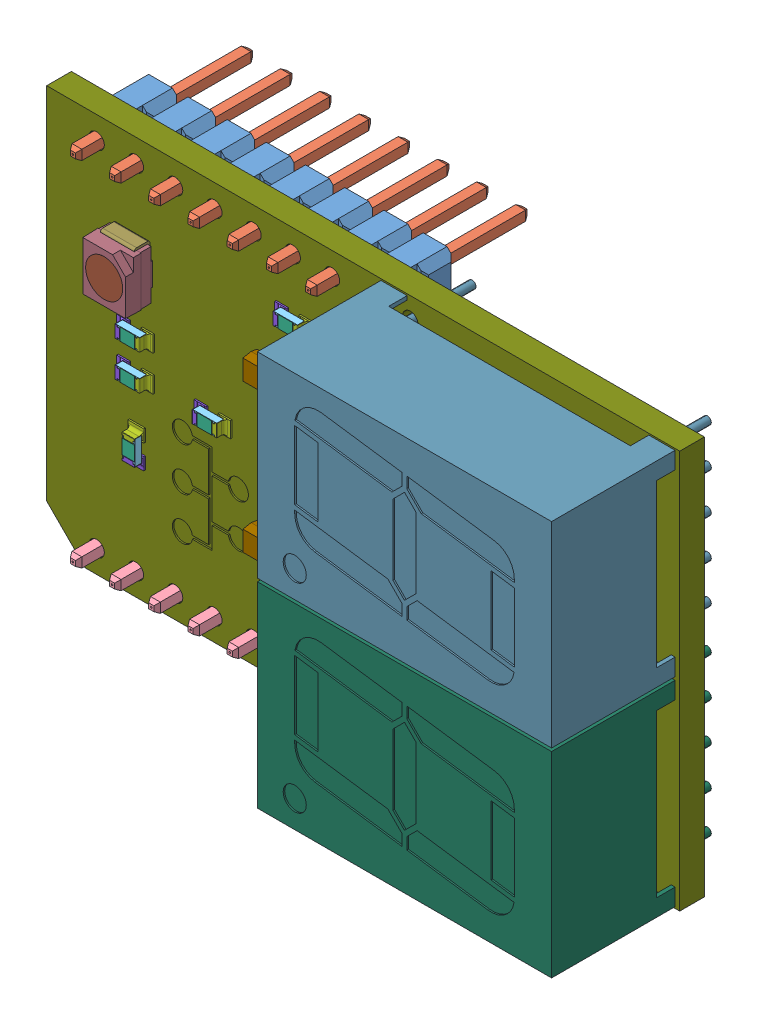
SolidWorks assembly mikroBUS_7_Seg_Click_Board, configuration Default. Lengths in mm.
Overall size (41 25.8 17.94).
120 component instances, 16 part files, 0 mates.
Components (placement in the parent):
- 7_Seg_Click_Board-1: 7_Seg_Click_Board [Default] at (-186.4371 -161.9019 60.2454) x (0 -1 0) z (0 0 1) size (25.8 41 17.94)
  - m20-9770842_asm.stp.1-1: m20-9770842_asm.stp.1 [Default] at (77.5496 46.3595 4.37) x (0 1 0) z (-1 0 0) size (20.32 11.48 2.54)
    - M20-977_ASM-1: M20-977_ASM [Default] at origin size (20.32 11.48 2.54)
      - M20-977-MOULD_2-1: M20-977-MOULD_2 [Default] at origin size (20.32 2.54 2.54)
      - M20-977-PIN.7-1: M20-977-PIN.7 [Default] at (2.54 -5.68 0) x (1 0 0) z (0 0 -1) size (0.64 11.48 0.64)
      - M20-977-PIN.7-2: M20-977-PIN.7 [Default] at (5.08 -5.68 0) x (1 0 0) z (0 0 -1) size (0.64 11.48 0.64)
      - M20-977-PIN.7-3: M20-977-PIN.7 [Default] at (7.62 -5.68 0) x (1 0 0) z (0 0 -1) size (0.64 11.48 0.64)
      - M20-977-PIN.7-4: M20-977-PIN.7 [Default] at (10.16 -5.68 0) x (1 0 0) z (0 0 -1) size (0.64 11.48 0.64)
      - M20-977-PIN.7-5: M20-977-PIN.7 [Default] at (12.7 -5.68 0) x (1 0 0) z (0 0 -1) size (0.64 11.48 0.64)
      - M20-977-PIN.7-6: M20-977-PIN.7 [Default] at (15.24 -5.68 0) x (1 0 0) z (0 0 -1) size (0.64 11.48 0.64)
      - M20-977-PIN.7-7: M20-977-PIN.7 [Default] at (17.78 -5.68 0) x (1 0 0) z (0 0 -1) size (0.64 11.48 0.64)
      - M20-977-PIN.7-8: M20-977-PIN.7 [Default] at (20.32 -5.68 0) x (1 0 0) z (0 0 -1) size (0.64 11.48 0.64)
  - m20-9770842_asm.stp-1: m20-9770842_asm.stp [Default] at (100.4096 46.3595 4.37) x (0 1 0) z (-1 0 0) size (20.32 11.48 2.54)
    - M20-977_ASM_2-1: M20-977_ASM_2 [Default] at origin size (20.32 11.48 2.54)
      - M20-977-MOULD-1: M20-977-MOULD [Default] at origin size (20.32 2.54 2.54)
      - M20-977-PIN.5-1: M20-977-PIN.5 [Default] at (2.54 -5.68 0) x (1 0 0) z (0 0 -1) size (0.64 11.48 0.64)
      - M20-977-PIN.5-2: M20-977-PIN.5 [Default] at (5.08 -5.68 0) x (1 0 0) z (0 0 -1) size (0.64 11.48 0.64)
      - M20-977-PIN.5-3: M20-977-PIN.5 [Default] at (7.62 -5.68 0) x (1 0 0) z (0 0 -1) size (0.64 11.48 0.64)
      - M20-977-PIN.5-4: M20-977-PIN.5 [Default] at (10.16 -5.68 0) x (1 0 0) z (0 0 -1) size (0.64 11.48 0.64)
      - M20-977-PIN.5-5: M20-977-PIN.5 [Default] at (12.7 -5.68 0) x (1 0 0) z (0 0 -1) size (0.64 11.48 0.64)
      - M20-977-PIN.5-6: M20-977-PIN.5 [Default] at (15.24 -5.68 0) x (1 0 0) z (0 0 -1) size (0.64 11.48 0.64)
      - M20-977-PIN.5-7: M20-977-PIN.5 [Default] at (17.78 -5.68 0) x (1 0 0) z (0 0 -1) size (0.64 11.48 0.64)
      - M20-977-PIN.5-8: M20-977-PIN.5 [Default] at (20.32 -5.68 0) x (1 0 0) z (0 0 -1) size (0.64 11.48 0.64)
  - arduino_uno_MLC0603.1.1.8-1: arduino_uno_MLC0603.1.1.8 [Default] at (93.2677 51.543 8.51) x (1 0 0) z (0 -1 0) size (2.36 0.6 1.03)
    - p4-1: p4 [Default] at origin size (1.55 0.45 0.8)
    - p3-1: p3 [Default] at origin size (1 0.03 0.8)
    - p2-1: p2 [Default] at origin size (0.8 0.6 1.03)
    - p1-1: p1 [Default] at origin size (0.8 0.6 1.03)
  - User_Library-arduino_uno_ssot3.1.1-1: User_Library-arduino_uno_ssot3.1.1 [Default] at (84.6189 60.8527 8.41) x (0 1 0) z (1 0 0) size (3 1.13 3.09)
  - Everlight_67-21SRC-TR8.STEP-1: Everlight_67-21SRC-TR8.STEP [Default] at (83.1478 51.2463 8.51) x (0 -1 0) z (-1 0 0) size (2.8 1.86 3.5)
    - User_Library-Everlight_67-21SRC-TR8-1: User_Library-Everlight_67-21SRC-TR8 [Default] at origin size (2.8 1.86 3.5)
      - User_Library-Everlight_67-21SRC-TR8_Imported_3-1: User_Library-Everlight_67-21SRC-TR8_Imported_3 [Default] at origin size (0.48 0.2 0.48)
      - User_Library-Everlight_67-21SRC-TR8_Imported_4-1: User_Library-Everlight_67-21SRC-TR8_Imported_4 [Default] at origin size (2.4 0.85 2.4)
      - User_Library-Everlight_67-21SRC-TR8_Imported-1: User_Library-Everlight_67-21SRC-TR8_Imported [Default] at origin size (2.2 1.01 3.5)
      - User_Library-Everlight_67-21SRC-TR8_Imported_2-1: User_Library-Everlight_67-21SRC-TR8_Imported_2 [Default] at origin size (2.8 1.8 3.2)
  - Disp_SA56-11.1-1: Disp_SA56-11.1 [Default] at (77.4495 69.2194 8.4773) size (12.7 19.05 12)
    - SW3dPS-Disp_SA56-11-1: SW3dPS-Disp_SA56-11 [Default] at origin size (12.7 19.05 12)
      - SW3dPS-Disp_SA56-11_Open_CASCADE_STEP_translator_6.2_78.2-1: SW3dPS-Disp_SA56-11_Open_CASCADE_STEP_translator_6.2_78.2 [Default] at origin size (12.7 19.05 12)
        - SW3dPS-Disp_SA56-11_Disp_SA56-12_2-1: SW3dPS-Disp_SA56-11_Disp_SA56-12_2 [Default] at (5.0801 7.6201 8.0327) x (1 0 0) z (0 -1 0) size (12.7 12 19.05)
  - Disp_SA56-11-1: Disp_SA56-11 [Default] at (90.3495 69.2194 8.4773) size (12.7 19.05 12)
    - SW3dPS-Disp_SA56-11_2-1: SW3dPS-Disp_SA56-11_2 [Default] at origin size (12.7 19.05 12)
      - SW3dPS-Disp_SA56-11_Open_CASCADE_STEP_translator_6.2_78.2_2-1: SW3dPS-Disp_SA56-11_Open_CASCADE_STEP_translator_6.2_78.2_2 [Default] at origin size (12.7 19.05 12)
        - SW3dPS-Disp_SA56-11_Disp_SA56-12-1: SW3dPS-Disp_SA56-11_Disp_SA56-12 [Default] at (5.0801 7.6201 8.0327) x (1 0 0) z (0 -1 0) size (12.7 12 19.05)
  - 7_Seg_Click_Board-1: 7_Seg_Click_Board [Default] at (0 0.5 0) size (25.8 41 1.6)
  - arduino_uno_MLC0603.1.1.8-2: arduino_uno_MLC0603.1.1.8 [Default] at (97.3056 65.7088 8.51) x (0 -1 0) z (-1 0 0) size (2.36 0.6 1.03)
    - p4-1: p4 [Default] at origin size (1.55 0.45 0.8)
    - p3-1: p3 [Default] at origin size (1 0.03 0.8)
    - p2-1: p2 [Default] at origin size (0.8 0.6 1.03)
    - p1-1: p1 [Default] at origin size (0.8 0.6 1.03)
  - arduino_uno_MLC0603.1.1.8-3: arduino_uno_MLC0603.1.1.8 [Default] at (97.3056 61.7088 8.51) x (0 -1 0) z (-1 0 0) size (2.36 0.6 1.03)
    - p4-1: p4 [Default] at origin size (1.55 0.45 0.8)
    - p3-1: p3 [Default] at origin size (1 0.03 0.8)
    - p2-1: p2 [Default] at origin size (0.8 0.6 1.03)
    - p1-1: p1 [Default] at origin size (0.8 0.6 1.03)
  - arduino_uno_MLC0603.1.1.8-4: arduino_uno_MLC0603.1.1.8 [Default] at (95.0056 65.7088 8.51) x (0 -1 0) z (-1 0 0) size (2.36 0.6 1.03)
    - p4-1: p4 [Default] at origin size (1.55 0.45 0.8)
    - p3-1: p3 [Default] at origin size (1 0.03 0.8)
    - p2-1: p2 [Default] at origin size (0.8 0.6 1.03)
    - p1-1: p1 [Default] at origin size (0.8 0.6 1.03)
  - arduino_uno_MLC0603.1.1.8-5: arduino_uno_MLC0603.1.1.8 [Default] at (92.7056 65.7088 8.51) x (0 -1 0) z (-1 0 0) size (2.36 0.6 1.03)
    - p4-1: p4 [Default] at origin size (1.55 0.45 0.8)
    - p3-1: p3 [Default] at origin size (1 0.03 0.8)
    - p2-1: p2 [Default] at origin size (0.8 0.6 1.03)
    - p1-1: p1 [Default] at origin size (0.8 0.6 1.03)
  - arduino_uno_MLC0603.1.1.8-6: arduino_uno_MLC0603.1.1.8 [Default] at (90.4056 65.7088 8.51) x (0 -1 0) z (-1 0 0) size (2.36 0.6 1.03)
    - p4-1: p4 [Default] at origin size (1.55 0.45 0.8)
    - p3-1: p3 [Default] at origin size (1 0.03 0.8)
    - p2-1: p2 [Default] at origin size (0.8 0.6 1.03)
    - p1-1: p1 [Default] at origin size (0.8 0.6 1.03)
  - arduino_uno_MLC0603.1.1.8-7: arduino_uno_MLC0603.1.1.8 [Default] at (90.4056 61.7088 8.51) x (0 -1 0) z (-1 0 0) size (2.36 0.6 1.03)
    - p4-1: p4 [Default] at origin size (1.55 0.45 0.8)
    - p3-1: p3 [Default] at origin size (1 0.03 0.8)
    - p2-1: p2 [Default] at origin size (0.8 0.6 1.03)
    - p1-1: p1 [Default] at origin size (0.8 0.6 1.03)
  - arduino_uno_MLC0603.1.1.8-8: arduino_uno_MLC0603.1.1.8 [Default] at (88.1056 65.7088 8.51) x (0 -1 0) z (-1 0 0) size (2.36 0.6 1.03)
    - p4-1: p4 [Default] at origin size (1.55 0.45 0.8)
    - p3-1: p3 [Default] at origin size (1 0.03 0.8)
    - p2-1: p2 [Default] at origin size (0.8 0.6 1.03)
    - p1-1: p1 [Default] at origin size (0.8 0.6 1.03)
  - arduino_uno_MLC0603.1.1.8-9: arduino_uno_MLC0603.1.1.8 [Default] at (88.1056 61.7088 8.51) x (0 -1 0) z (-1 0 0) size (2.36 0.6 1.03)
    - p4-1: p4 [Default] at origin size (1.55 0.45 0.8)
    - p3-1: p3 [Default] at origin size (1 0.03 0.8)
    - p2-1: p2 [Default] at origin size (0.8 0.6 1.03)
    - p1-1: p1 [Default] at origin size (0.8 0.6 1.03)
  - arduino_uno_MLC0603.1.1.8-10: arduino_uno_MLC0603.1.1.8 [Default] at (85.8056 65.7088 8.51) x (0 -1 0) z (-1 0 0) size (2.36 0.6 1.03)
    - p4-1: p4 [Default] at origin size (1.55 0.45 0.8)
    - p3-1: p3 [Default] at origin size (1 0.03 0.8)
    - p2-1: p2 [Default] at origin size (0.8 0.6 1.03)
    - p1-1: p1 [Default] at origin size (0.8 0.6 1.03)
  - arduino_uno_MLC0603.1.1.8-11: arduino_uno_MLC0603.1.1.8 [Default] at (83.5056 65.7088 8.51) x (0 -1 0) z (-1 0 0) size (2.36 0.6 1.03)
    - p4-1: p4 [Default] at origin size (1.55 0.45 0.8)
    - p3-1: p3 [Default] at origin size (1 0.03 0.8)
    - p2-1: p2 [Default] at origin size (0.8 0.6 1.03)
    - p1-1: p1 [Default] at origin size (0.8 0.6 1.03)
  - arduino_uno_MLC0603.1.1.8-12: arduino_uno_MLC0603.1.1.8 [Default] at (81.2056 65.7088 8.51) x (0 -1 0) z (-1 0 0) size (2.36 0.6 1.03)
    - p4-1: p4 [Default] at origin size (1.55 0.45 0.8)
    - p3-1: p3 [Default] at origin size (1 0.03 0.8)
    - p2-1: p2 [Default] at origin size (0.8 0.6 1.03)
    - p1-1: p1 [Default] at origin size (0.8 0.6 1.03)
  - arduino_uno_MLC0603.1.1.8-13: arduino_uno_MLC0603.1.1.8 [Default] at (81.2056 61.7088 8.51) x (0 -1 0) z (-1 0 0) size (2.36 0.6 1.03)
    - p4-1: p4 [Default] at origin size (1.55 0.45 0.8)
    - p3-1: p3 [Default] at origin size (1 0.03 0.8)
    - p2-1: p2 [Default] at origin size (0.8 0.6 1.03)
    - p1-1: p1 [Default] at origin size (0.8 0.6 1.03)
  - arduino_uno_MLC0603.1.1.8-14: arduino_uno_MLC0603.1.1.8 [Default] at (89.3331 51.4771 8.51) x (0 -1 0) z (-1 0 0) size (2.36 0.6 1.03)
    - p4-1: p4 [Default] at origin size (1.55 0.45 0.8)
    - p3-1: p3 [Default] at origin size (1 0.03 0.8)
    - p2-1: p2 [Default] at origin size (0.8 0.6 1.03)
    - p1-1: p1 [Default] at origin size (0.8 0.6 1.03)
  - arduino_uno_MLC0603.1.1.8-15: arduino_uno_MLC0603.1.1.8 [Default] at (89.3331 56.4771 8.51) x (0 -1 0) z (-1 0 0) size (2.36 0.6 1.03)
    - p4-1: p4 [Default] at origin size (1.55 0.45 0.8)
    - p3-1: p3 [Default] at origin size (1 0.03 0.8)
    - p2-1: p2 [Default] at origin size (0.8 0.6 1.03)
    - p1-1: p1 [Default] at origin size (0.8 0.6 1.03)
  - arduino_uno_MLC0603.1.1.8-16: arduino_uno_MLC0603.1.1.8 [Default] at (87.0331 51.4771 8.51) x (0 -1 0) z (-1 0 0) size (2.36 0.6 1.03)
    - p4-1: p4 [Default] at origin size (1.55 0.45 0.8)
    - p3-1: p3 [Default] at origin size (1 0.03 0.8)
    - p2-1: p2 [Default] at origin size (0.8 0.6 1.03)
    - p1-1: p1 [Default] at origin size (0.8 0.6 1.03)
  - User_Library-arduino_uno_ssot3.1.1-2: User_Library-arduino_uno_ssot3.1.1 [Default] at (94.2189 60.8527 8.41) x (0 1 0) z (1 0 0) size (3 1.13 3.09)
